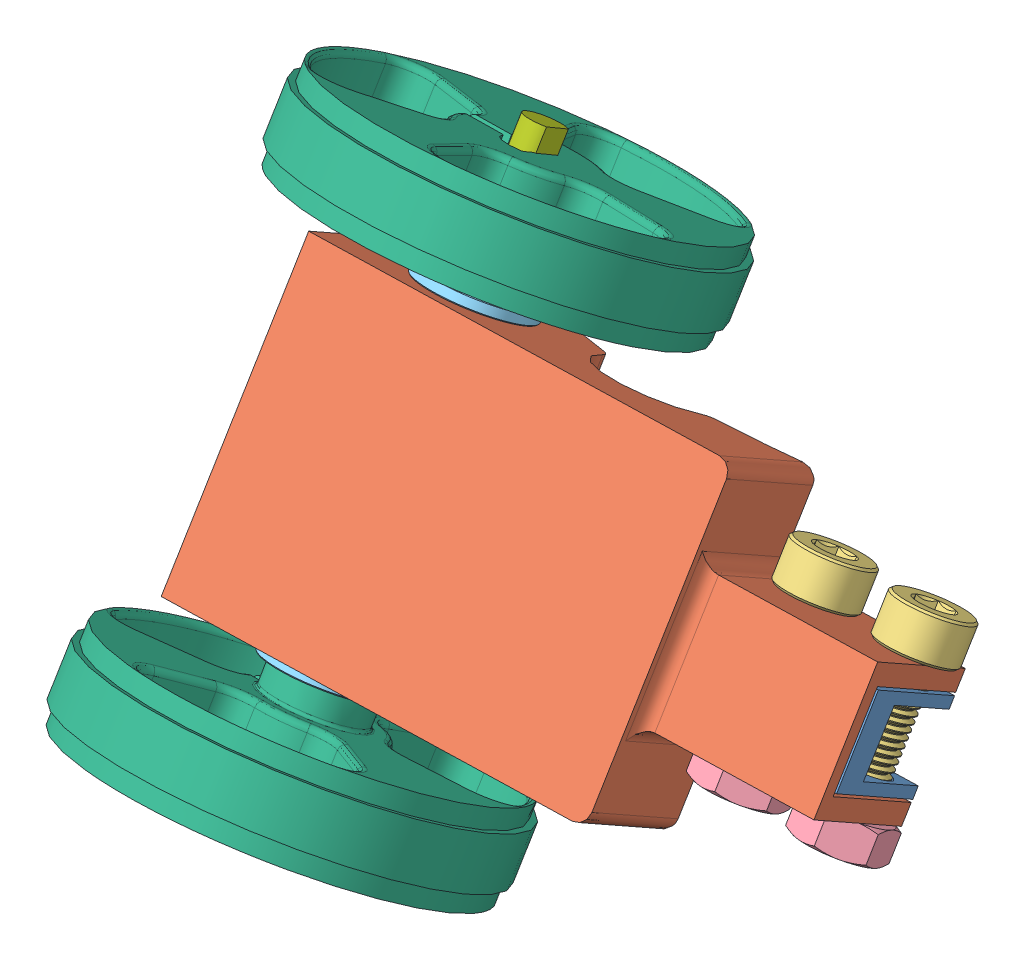
SolidWorks assembly Top Wheel Housing, configuration Default. Lengths in mm.
Overall size (52.78 51.76 46.43).
11 component instances, 7 part files, 23 mates.
Components (placement in the parent):
- Motor Base2-1: Motor Base2 [Default] at (-47.7677 32.3427 44.0293) x (0 -0.854612 0.519267) z (0.996377 -0.044164 -0.072686) size (6.5 8.02 14.6)
- Top Housing-1: Top Housing [Default] at (-47.6481 34.4272 47.46) x (-0.996377 0.044164 0.072686) z (0 -0.854612 0.519267) size (45 10.72 22.9)
- 91290A115_Black-Oxide Alloy Steel Socket Head Screw-1: 91290A115_Black-Oxide Alloy Steel Socket Head Screw [91290A115] at (-42.6366 27.0177 44.9907) x (0.860754 -0.264318 -0.435016) z (0 -0.854612 0.519267) size (5.5 5.5 13.21)
- 91290A115_Black-Oxide Alloy Steel Socket Head Screw-2: 91290A115_Black-Oxide Alloy Steel Socket Head Screw [91290A115] at (-50.1094 27.3489 45.5358) x (0.860754 -0.264318 -0.435016) z (0 -0.854612 0.519267) size (5.5 5.5 13.21)
- 90592A085_STEEL HEX NUT-1: 90592A085_STEEL HEX NUT [90592A085] at (-42.6366 26.0776 45.5619) x (0.969965 -0.126309 -0.207879) z (0.243244 0.503671 0.828944) size (5.5 2.79 6.35)
- 90592A085_STEEL HEX NUT-2: 90592A085_STEEL HEX NUT [90592A085] at (-50.1094 26.4089 46.107) x (0.969965 -0.126309 -0.207879) z (0.243244 0.503671 0.828944) size (5.5 2.79 6.35)
- 57155K427_Stainless Steel Ball Bearing-1: 57155K427_Stainless Steel Ball Bearing [57155K427] at (-76.6397 24.7116 53.1351) x (0.326252 0.490854 0.80785) z (0 0.854612 -0.519267) size (8.1 8.1 2)
- 57155K427_Stainless Steel Ball Bearing-2: 57155K427_Stainless Steel Ball Bearing [57155K427] at (-76.6397 43.9404 41.4516) x (-0.851893 0.271949 0.447574) z (0 -0.854612 0.519267) size (8.1 8.1 2)
- Outer Wheel-1: Outer Wheel [Default] at (-76.6641 19.9228 55.4605) x (0.048793 0.518649 0.853594) z (-0.998809 0.025337 0.041699) size (28.6 8.63 28.6)
- Outer Wheel-2: Outer Wheel [Default] at (-76.6153 48.7291 39.1263) x (-0.048793 -0.518649 -0.853594) z (-0.998809 0.025337 0.041699) size (28.6 8.63 28.6)
- Dshaftd3l40-1: Dshaftd3l40 [Default] at (-76.6397 34.326 47.2934) x (0 -0.854612 0.519267) z (0.048793 0.518649 0.853594) size (45 2.4 2.9)
Mates (geometry in assembly coordinates):
- Coincident290: coincident aligned: plane of Motor Base2-1 through (-47.7677 32.3427 44.0293) normal (0 -0.854612 0.519267); plane of Top Housing-1 through (-47.6481 34.4272 47.46) normal (0 -0.854612 0.519267)
- Concentric193: concentric aligned: cylinder of Motor Base2-1 through (-42.6366 28.556 44.056) axis (0 0.854612 -0.519267) radius 1.625; cylinder of Top Housing-1 through (-42.6366 21.5482 48.314) axis (0 0.854612 -0.519267) radius 1.51
- Concentric194: concentric aligned: cylinder of Motor Base2-1 through (-50.1094 28.8872 44.6011) axis (0 0.854612 -0.519267) radius 1.625; cylinder of Top Housing-1 through (-50.1094 21.8794 48.8591) axis (0 0.854612 -0.519267) radius 1.51
- Concentric195: concentric anti-aligned: cylinder of Top Housing-1 through (-42.6366 21.5482 48.314) axis (0 0.854612 -0.519267) radius 1.51; cylinder of 91290A115_Black-Oxide Alloy Steel Socket Head Screw-1 through (-42.6366 38.1277 38.2402) axis (0 -0.854612 0.519267) radius 2.75
- Coincident291: coincident anti-aligned: plane of Top Housing-1 through (-55.803 34.8393 38.6056) normal (0 0.854612 -0.519267); plane of 91290A115_Black-Oxide Alloy Steel Socket Head Screw-1 through (-42.6366 35.5638 39.798) normal (0 -0.854612 0.519267)
- Concentric196: concentric anti-aligned: cylinder of Top Housing-1 through (-50.1094 21.8794 48.8591) axis (0 0.854612 -0.519267) radius 1.51; cylinder of 91290A115_Black-Oxide Alloy Steel Socket Head Screw-2 through (-50.1094 38.4589 38.7853) axis (0 -0.854612 0.519267) radius 2.75
- Coincident292: coincident anti-aligned: plane of Top Housing-1 through (-55.803 34.8393 38.6056) normal (0 0.854612 -0.519267); plane of 91290A115_Black-Oxide Alloy Steel Socket Head Screw-2 through (-50.1094 35.8951 40.3431) normal (0 -0.854612 0.519267)
- Concentric197: concentric aligned: cylinder of 91290A115_Black-Oxide Alloy Steel Socket Head Screw-2 through (-50.1094 38.4589 38.7853) axis (0 -0.854612 0.519267) radius 2.75; cone of 90592A085_STEEL HEX NUT-2 through (-50.1094 27.4344 45.4839) axis (0 -0.854612 0.519267)
- Coincident293: coincident anti-aligned: plane of Top Housing-1 through (-55.803 26.3787 43.7464) normal (0 -0.854612 0.519267); plane of 90592A085_STEEL HEX NUT-2 through (-53.163 26.9821 44.7394) normal (0 0.854612 -0.519267)
- Concentric198: concentric aligned: cylinder of 91290A115_Black-Oxide Alloy Steel Socket Head Screw-1 through (-42.6366 38.1277 38.2402) axis (0 -0.854612 0.519267) radius 2.75; cone of 90592A085_STEEL HEX NUT-1 through (-42.6366 27.1032 44.9387) axis (0 -0.854612 0.519267)
- Coincident294: coincident anti-aligned: plane of Top Housing-1 through (-55.803 26.3787 43.7464) normal (0 -0.854612 0.519267); plane of 90592A085_STEEL HEX NUT-1 through (-45.6902 26.6508 44.1943) normal (0 0.854612 -0.519267)
- Coincident295: coincident anti-aligned: plane of Top Housing-1 through (-53.8102 40.306 35.085) normal (0 0.854612 -0.519267); plane of 57155K427_Stainless Steel Ball Bearing-2 through (-78.7607 42.3197 38.3992) normal (0 -0.854612 0.519267)
- Concentric199: concentric anti-aligned: cylinder of Top Housing-1 through (-76.6397 24.5407 53.239) axis (0 0.854612 -0.519267) radius 3.6; cylinder of 57155K427_Stainless Steel Ball Bearing-2 through (-76.6397 43.9404 41.4516) axis (0 -0.854612 0.519267) radius 3.5
- Coincident296: coincident anti-aligned: plane of Top Housing-1 through (-53.8102 20.7354 46.9762) normal (0 -0.854612 0.519267); plane of 57155K427_Stainless Steel Ball Bearing-1 through (-72.8113 23.8546 52.1098) normal (0 0.854612 -0.519267)
- Concentric200: concentric aligned: cylinder of Top Housing-1 through (-76.6397 24.5407 53.239) axis (0 0.854612 -0.519267) radius 3.6; cylinder of 57155K427_Stainless Steel Ball Bearing-1 through (-76.6397 24.7116 53.1351) axis (0 0.854612 -0.519267) radius 3.5
- Concentric201: concentric aligned: cylinder of 57155K427_Stainless Steel Ball Bearing-2 through (-76.6397 43.9404 41.4516) axis (0 -0.854612 0.519267) radius 1.5; cylinder of Dshaftd3l40-1 through (-76.6397 53.5547 35.6099) axis (0 -0.854612 0.519267) radius 1.45
- Coincident297: coincident aligned: plane of Top Housing-1 through (-47.6481 34.4272 47.46) normal (0 -0.854612 0.519267); plane of Dshaftd3l40-1 through (-76.6397 34.326 47.2934) normal (0 -0.854612 0.519267)
- Coincident298: coincident anti-aligned: plane of 57155K427_Stainless Steel Ball Bearing-2 through (-78.1585 43.5121 38.8211) normal (0 0.854612 -0.519267); plane of Outer Wheel-2 through (-73.1195 44.9656 41.2132) normal (0 -0.854612 0.519267)
- Concentric202: concentric aligned: cylinder of Outer Wheel-2 through (-76.6397 52.1446 36.4667) axis (0 -0.854612 0.519267) radius 1.55; cylinder of Dshaftd3l40-1 through (-76.6397 53.5547 35.6099) axis (0 -0.854612 0.519267) radius 1.45
- Parallel1: parallel anti-aligned: plane of Outer Wheel-2 through (-75.6787 53.314 38.3912) normal (-0.998809 0.025337 0.041699); plane of Dshaftd3l40-1 through (-75.6908 53.5307 35.5703) normal (0.998809 -0.025337 -0.041699)
- Concentric203: concentric anti-aligned: cylinder of Outer Wheel-1 through (-76.6397 16.5073 58.1201) axis (0 0.854612 -0.519267) radius 1.55; cylinder of Dshaftd3l40-1 through (-76.6397 53.5547 35.6099) axis (0 -0.854612 0.519267) radius 1.45
- Coincident300: coincident anti-aligned: plane of 57155K427_Stainless Steel Ball Bearing-1 through (-73.8984 23.3657 52.8458) normal (0 -0.854612 0.519267); plane of Outer Wheel-1 through (-73.1682 23.509 53.0817) normal (0 0.854612 -0.519267)
- Parallel2: parallel anti-aligned: plane of Outer Wheel-1 through (-75.9027 15.2949 56.1247) normal (-0.998809 0.025337 0.041699); plane of Dshaftd3l40-1 through (-75.6908 53.5307 35.5703) normal (0.998809 -0.025337 -0.041699)
